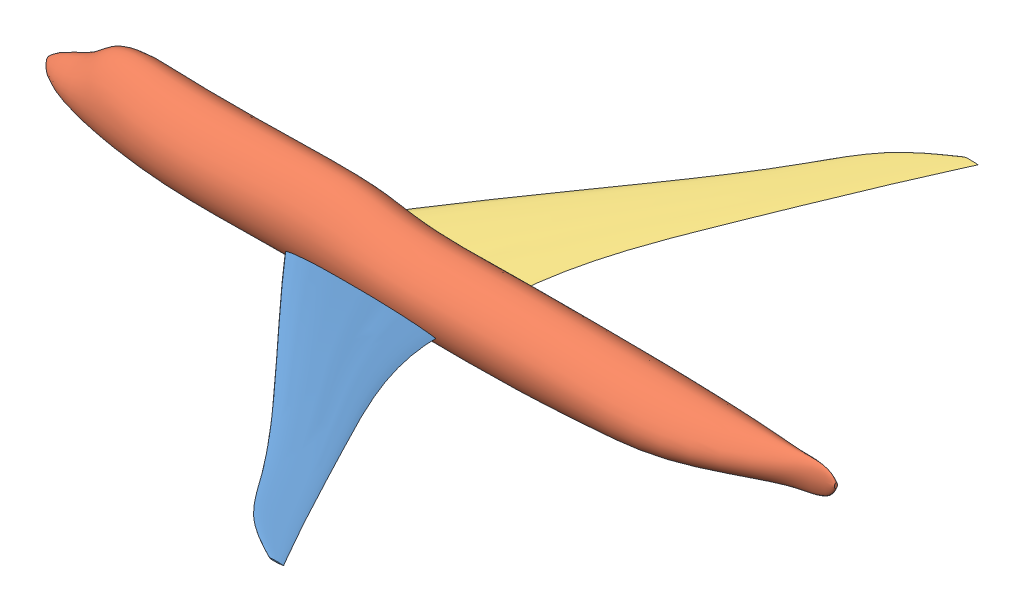
SolidWorks assembly Assem1, configuration Default. Lengths in mm.
Overall size (656 375 664.45).
3 component instances, 3 part files, 3 mates.
Components (placement in the parent):
- b747-8-left-wing-notfinished-1: b747-8-left-wing-notfinished [Default] at origin size (656 375 664.45)
- fuselage-1: fuselage [Default] at (-87.376 -2 -8) size (264.87 30.68 24.71)
- Mirrorb747-8-left-wing-notfinished-2: Mirrorb747-8-left-wing-notfinished [Default] at (0 0 -16) size (106.59 17.43 107.34)
Mates (geometry in assembly coordinates):
- Coincident1: coincident: plane of fuselage-1 through (-87.376 -2 0) normal (0 0 1); plane of assembly through (0 0 0) normal (0 0 1)
- Coincident2: coincident: plane of fuselage-1 through (-87.376 0 -8) normal (0 1 0); plane of assembly through (0 0 0) normal (0 1 0)
- Coincident3: coincident: plane of fuselage-1 through (0 -2 -8) normal (1 0 0); plane of assembly through (0 0 0) normal (1 0 0)
